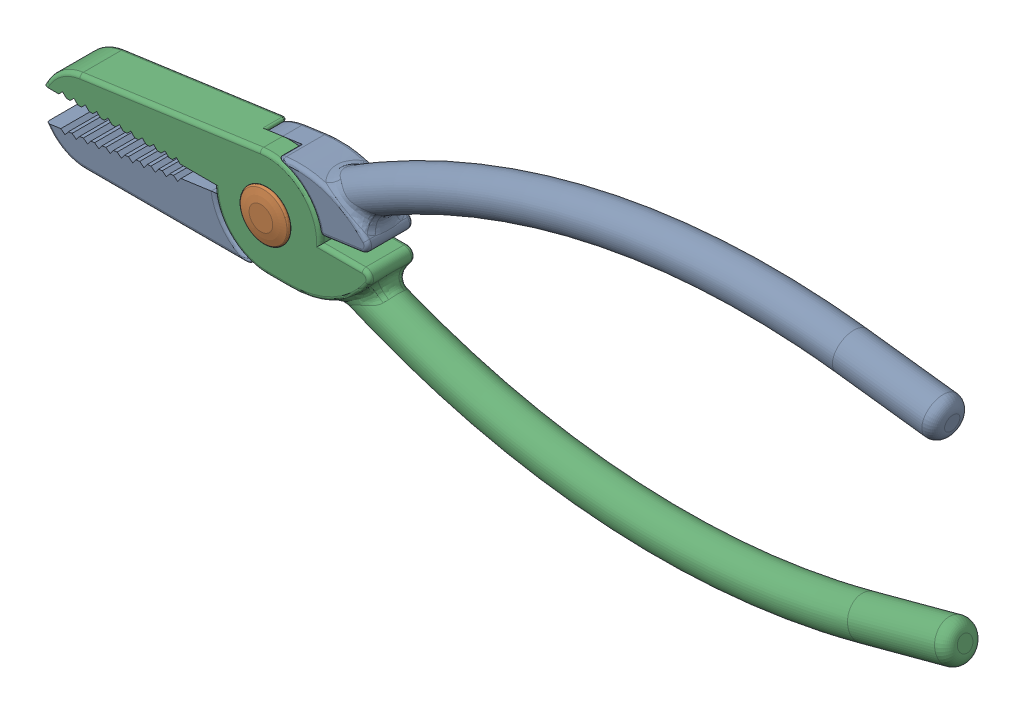
SolidWorks assembly 01_B_CSWA_Lvl9, configuration Default. Lengths in mm.
Overall size (241.53 86.04 15.4).
3 component instances, 3 part files, 5 mates.
Components (placement in the parent):
- Plier-Handle-1: Plier-Handle [Default] x (0.990268 0.139173 0) z (0 0 -1) size (237.62 44.74 12.21)
- Plier-Joint-1: Plier-Joint [Default] x (0.530011 0.847991 0) z (0 0 -1) size (13 13 15.4)
- Plier-Handle-Base-2: Plier-Handle-Base [Default] at origin size (237.62 44.74 12.21)
Mates (geometry in assembly coordinates):
- Coincident2: coincident anti-aligned: plane of Plier-Handle-1 through (0 0 -6) normal (0 0 -1); circle of Plier-Joint-1
- Concentric2: concentric aligned: cylinder of Plier-Handle-1 through (0 0 -6) axis (0 0 1) radius 3; cylinder of Plier-Joint-1 through (0 0 7.946) axis (0 0 1) radius 2.5
- Concentric5: concentric aligned: cylinder of Plier-Joint-1 through (0 0 7.946) axis (0 0 1) radius 2.5; circle of Plier-Handle-Base-2
- Coincident5: coincident anti-aligned: plane of Plier-Joint-1 through (0 0 6) normal (0 0 -1); plane of Plier-Handle-Base-2 through (0 0 6) normal (0 0 1)
- Angle2: planar angle = 0.139626 rad anti-aligned: plane of Plier-Handle-1 through (0 0 -6) normal (0.139173 -0.990268 0); plane of Plier-Handle-Base-2 through (0 0 6) normal (0 1 0)
